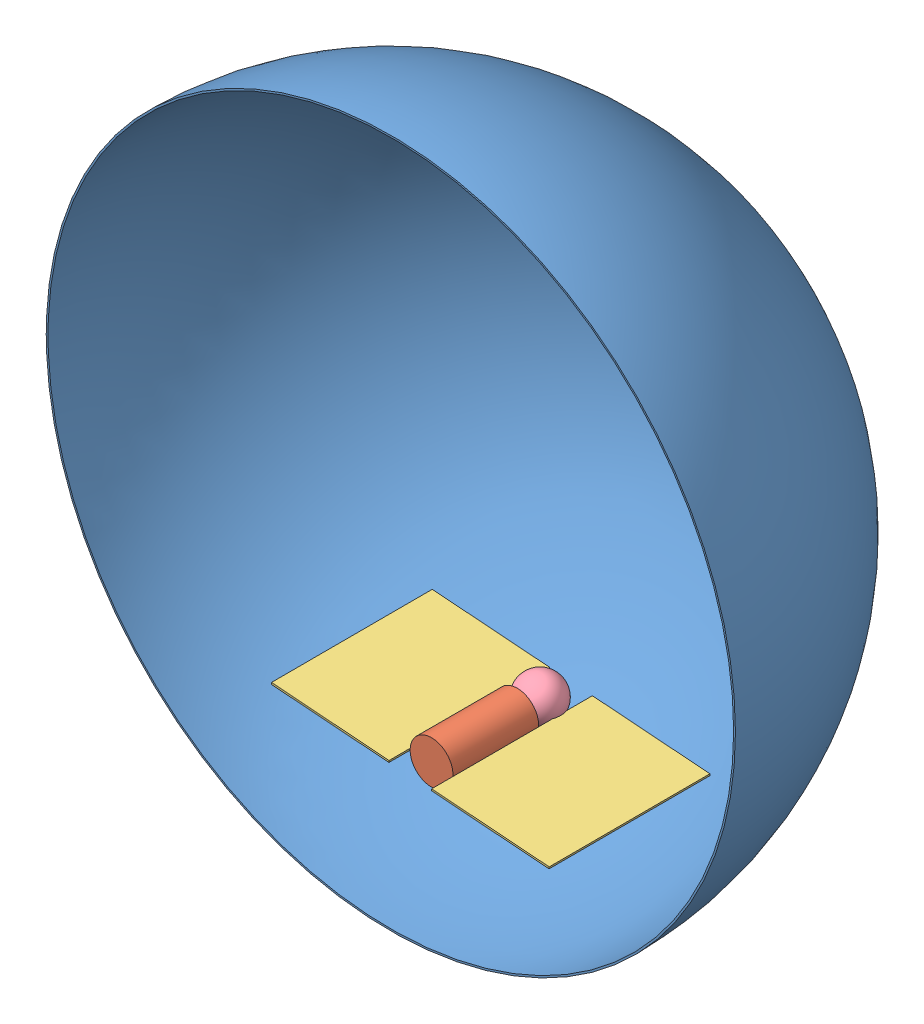
SolidWorks assembly Assem2, configuration Default. Lengths in mm.
Overall size (9804.4 9804.4 4902.2).
6 component instances, 4 part files, 1 mates.
Components (placement in the parent):
- dome_stand_in-1: dome_stand_in [Default] at (6074.8468 8725.6749 3799.2472) size (9804.4 9804.4 4902.2)
- rough_body-1: rough_body [Default] at (5783.2271 5111.0464 6861.4382) size (3951.55 667.68 2286.58)
  - body_stand_in-1: body_stand_in [Default] at (260.872 470.1823 1151.1497) size (609.6 609.6 1219.2)
  - wing_stand_in-1: wing_stand_in [Default] at (-1715.5894 597.5276 -779.4942) x (0.997171 -0.075171 -0.000136) z (0.000006 -0.001735 0.999998) size (1676.4 25.4 2286)
  - wing_stand_in-2: wing_stand_in [Default] at (562.3795 425.8034 -779.8057) x (0.997171 -0.075171 -0.000136) z (0.000006 -0.001735 0.999998) size (1676.4 25.4 2286)
  - head_stand_in-1: head_stand_in [Default] at (286.6823 528.2667 -7.4901) size (609.6 609.6 609.6)
Mates (geometry in assembly coordinates):
- Distance1: distance = 609.6 mm: plane of rough_body-1/body_stand_in-1 through (6044.0992 5581.2287 8066.4472) normal (0 0 1); plane of dome_stand_in-1 through (10951.6468 8725.6749 8676.0472) normal (0 0 1)
